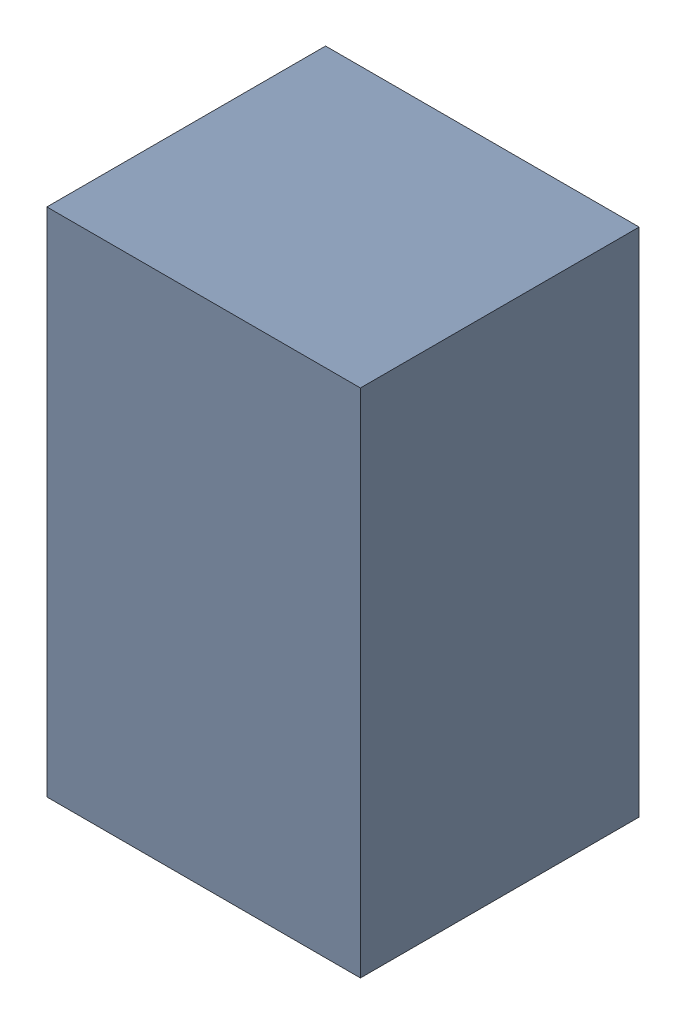
SolidWorks assembly CP3, configuration Default. Lengths in mm.
Overall size (1.35 2.2 1.2).
2 component instances, 1 part files, 0 mates.
Components (placement in the parent):
- 407985568-1: 407985568 [Default] at (80.01 61.3918 -1.6039) size (1.35 2.2 1.2)
  - Extruded_3-1: Extruded_3 [Default] at origin size (1.35 2.2 1.2)
